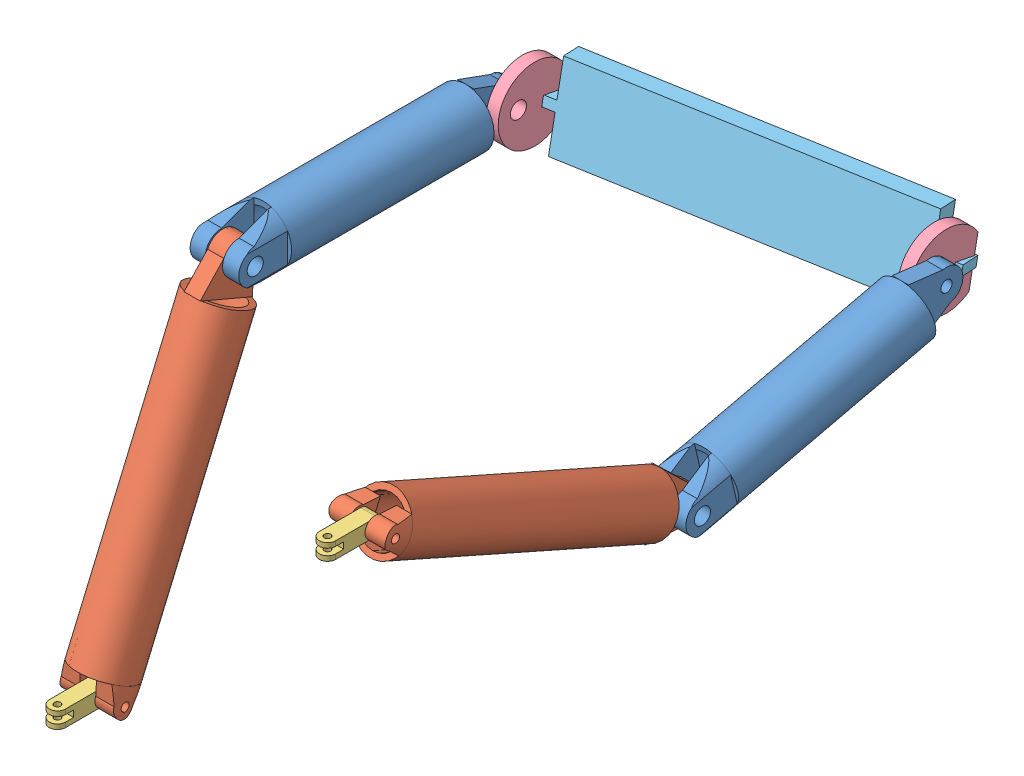
SolidWorks assembly arm, configuration Default. Lengths in mm.
Overall size (520.24 525.99 838.37).
9 component instances, 5 part files, 18 mates.
Components (placement in the parent):
- Part1-1: Part1 [Default] at (1.7007 7.5025 -130.9946) size (70 90 415.88)
- hand1-1: hand1 [Default] at (1.7007 -29.2674 174.7525) x (1 0 0) z (0 -0.919249 0.393677) size (70 70 453.16)
- wr1-1: wr1 [Default] at (-8.2993 -368.5821 310.3496) size (20 20 71)
- handsupp1-1: handsupp1 [Default] at (11.7007 3.6734 -191.0727) x (0 -0.187334 -0.982296) z (1 0 0) size (79 90 15)
- handsupp2-2: handsupp2 [Default] at (10.2961 51.4515 -207.4484) x (0.974733 -0.041846 -0.21942) z (0.223375 0.182601 0.957476) size (450 100 25)
- Part1-2: Part1 [Default] at (451.9368 -19.4072 -225.5126) x (1 0 0) z (0 -0.227086 0.973875) size (70 90 415.88)
- hand1-2: hand1 [Default] at (451.9368 -69.0677 93.4862) x (1 0 0) z (0 0.40486 0.914379) size (70 70 453.16)
- handsupp1-2: handsupp1 [Default] at (441.9368 -14.1528 -284.5457) x (0 -0.187334 -0.982296) z (-1 0 0) size (79 90 15)
- wr1-2: wr1 [Default] at (441.9368 94.7789 426.9501) size (20 20 71)
Mates (geometry in assembly coordinates):
- Coincident2: coincident anti-aligned: plane of Part1-1 through (11.7007 77.5025 182.9887) normal (-1 0 0); plane of hand1-1 through (11.7007 7.5025 159.0054) normal (1 0 0)
- Concentric1: concentric aligned: circle of Part1-1; circle of hand1-1
- Coincident3: coincident anti-aligned: plane of hand1-1 through (11.7007 -365.0245 394.6925) normal (-1 0 0); plane of wr1-1 through (11.7007 -368.5821 385.3496) normal (1 0 0)
- Concentric2: concentric anti-aligned: cylinder of hand1-1 through (-33.2993 -378.5821 324.3496) axis (1 0 0) radius 5; cylinder of wr1-1 through (61.7007 -378.5821 324.3496) axis (-1 0 0) radius 4
- Concentric3: concentric aligned: circle of Part1-1; circle of handsupp1-1
- Coincident8: coincident anti-aligned: plane of Part1-1 through (11.7007 7.5025 -170.9946) normal (1 0 0); plane of handsupp1-1 through (11.7007 3.6734 -191.0727) normal (-1 0 0)
- Concentric5: concentric anti-aligned: cylinder of Part1-1 through (-8.2993 7.5025 -170.9946) axis (1 0 0) radius 7; cylinder of handsupp1-1 through (26.7007 7.5025 -170.9946) axis (-1 0 0) radius 10
- Coincident9: coincident anti-aligned: plane of handsupp1-1 through (26.7007 3.1978 -225.5948) normal (0 -0.982296 0.187334); plane of handsupp2-2 through (30.6031 -0.3289 -244.0874) normal (0 0.982296 -0.187334)
- Coincident12: coincident aligned: circle of handsupp1-1; circle of handsupp2-2
- Parallel2: parallel anti-aligned: plane of handsupp1-1 through (26.7007 3.6734 -191.0727) normal (1 0 0); plane of handsupp1-2 through (426.9368 -14.1528 -284.5457) normal (-1 0 0)
- Coincident14: coincident anti-aligned: plane of handsupp2-2 through (439.9908 -17.9041 -336.2439) normal (0 0.982296 -0.187334); plane of handsupp1-2 through (426.9368 -10.1324 -295.4927) normal (0 -0.982296 0.187334)
- Coincident15: coincident aligned: circle of handsupp2-2; circle of handsupp1-2
- Concentric6: concentric anti-aligned: circle of Part1-2; circle of handsupp1-2
- Coincident16: coincident anti-aligned: plane of Part1-2 through (441.9368 -10.3237 -264.4676) normal (-1 0 0); plane of handsupp1-2 through (441.9368 -14.1528 -284.5457) normal (1 0 0)
- Concentric7: concentric anti-aligned: circle of Part1-2; circle of hand1-2
- Coincident18: coincident anti-aligned: plane of Part1-2 through (461.9368 -22.5372 96.1637) normal (-1 0 0); plane of hand1-2 through (461.9368 -85.2621 56.911) normal (1 0 0)
- Concentric8: concentric aligned: circle of hand1-2; cylinder of wr1-2 through (511.9368 84.7789 440.9501) axis (-1 0 0) radius 4
- Coincident19: coincident anti-aligned: plane of hand1-2 through (461.9368 154.9513 426.5356) normal (-1 0 0); plane of wr1-2 through (461.9368 94.7789 501.9501) normal (1 0 0)
